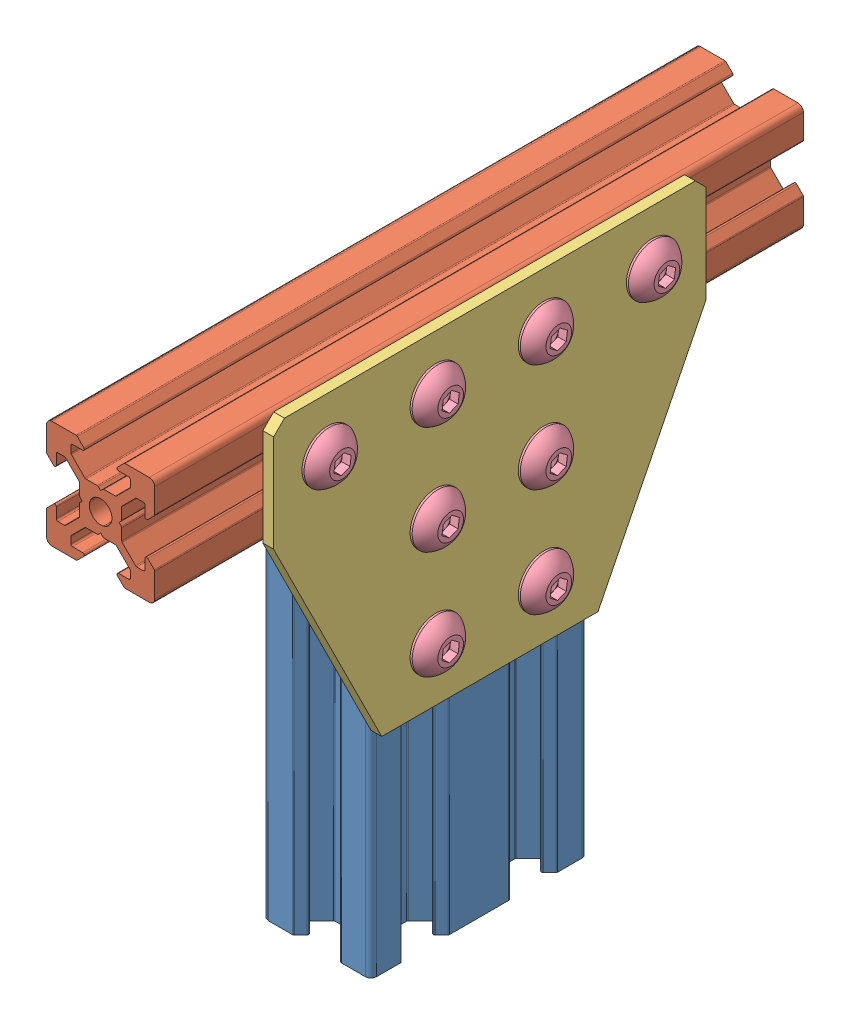
SolidWorks assembly Т-пластина 20 серия 4х3 8отв 60х80х2 усил СБ, configuration По умолчанию. Lengths in mm.
Overall size (24.75 100 120).
11 component instances, 4 part files, 25 mates.
Components (placement in the parent):
- 204090-1: 204090 [По умолчанию] at (-10 0 -10) x (0 0 -1) z (0 1 0) size (40 20 80)
- 2020100-1: 2020100 [По умолчанию] at (-10 90 -80) size (20 20 120)
- Т-пластина 20 серия 4х3 8отв 60х80х2 усил.-1: Т-пластина 20 серия 4х3 8отв 60х80х2 усил. [По умолчанию] at (0 40 -20) x (0 0 -1) z (0 -1 0) size (80 2 60)
- socket button head screw_iso-1: socket button head screw_iso [ISO 7380 - M5 x 10 - 10N] at (4.75 90 10) x (-1 0 0) z (0 0.924225 0.381849) size (12.75 9.5 9.5)
- socket button head screw_iso-2: socket button head screw_iso [ISO 7380 - M5 x 10 - 10N] at (4.75 90 -10) x (-1 0 0) z (0 0.924225 0.381849) size (12.75 9.5 9.5)
- socket button head screw_iso-3: socket button head screw_iso [ISO 7380 - M5 x 10 - 10N] at (4.75 90 -30) x (-1 0 0) z (0 0.924225 0.381849) size (12.75 9.5 9.5)
- socket button head screw_iso-4: socket button head screw_iso [ISO 7380 - M5 x 10 - 10N] at (4.75 90 -50) x (-1 0 0) z (0 0.924225 0.381849) size (12.75 9.5 9.5)
- socket button head screw_iso-5: socket button head screw_iso [ISO 7380 - M5 x 10 - 10N] at (4.75 70 -10) x (-1 0 0) z (0 0.924225 0.381849) size (12.75 9.5 9.5)
- socket button head screw_iso-6: socket button head screw_iso [ISO 7380 - M5 x 10 - 10N] at (4.75 70 -30) x (-1 0 0) z (0 0.924225 0.381849) size (12.75 9.5 9.5)
- socket button head screw_iso-7: socket button head screw_iso [ISO 7380 - M5 x 10 - 10N] at (4.75 50 -10) x (-1 0 0) z (0 0.924225 0.381849) size (12.75 9.5 9.5)
- socket button head screw_iso-8: socket button head screw_iso [ISO 7380 - M5 x 10 - 10N] at (4.75 50 -30) x (-1 0 0) z (0 0.924225 0.381849) size (12.75 9.5 9.5)
Mates (geometry in assembly coordinates):
- Совпадение1: coincident anti-aligned: plane of 204090-1 through (-10 0 -10) normal (0 -1 0)
- Совпадение2: coincident aligned: plane of 204090-1 through (0 80 -25.6) normal (1 0 0)
- Совпадение3: coincident aligned: plane of 204090-1 through (-20 80 0) normal (0 0 1)
- Совпадение4: coincident anti-aligned: plane of 204090-1 through (-10 80 -10) normal (0 1 0); plane of 2020100-1 through (0 80 40) normal (0 -1 0)
- Совпадение5: coincident aligned: plane of 204090-1 through (0 80 0) normal (1 0 0); plane of 2020100-1 through (0 80 40) normal (1 0 0)
- Совпадение6: coincident anti-aligned: plane of 204090-1 through (0 80 -25.6) normal (1 0 0); plane of Т-пластина 20 серия 4х3 8отв 60х80х2 усил.-1 through (0 40 -20) normal (-1 0 0)
- Совпадение7: coincident aligned: plane of 2020100-1 through (0 100 40) normal (0 1 0); plane of Т-пластина 20 серия 4х3 8отв 60х80х2 усил.-1 through (2 100 20) normal (0 1 0)
- Совпадение8: coincident: plane of 204090-1 through (0 80 0) normal (0 0 1); line of Т-пластина 20 серия 4х3 8отв 60х80х2 усил.-1 through (2 40 0) axis (-1 0 0)
- Расстояние1: distance = 20 mm aligned: plane of Т-пластина 20 серия 4х3 8отв 60х80х2 усил.-1 through (2 100 20) normal (0 0 1); plane of 2020100-1 through (-10 90 40) normal (0 0 1)
- Концентричный1: concentric aligned: cylinder of Т-пластина 20 серия 4х3 8отв 60х80х2 усил.-1 through (2 90 10) axis (1 0 0) radius 2.75; cylinder of socket button head screw_iso-1 through (4.75 90 10) axis (1 0 0) radius 4.75
- Совпадение10: coincident anti-aligned: plane of Т-пластина 20 серия 4х3 8отв 60х80х2 усил.-1 through (2 40 -20) normal (1 0 0); plane of socket button head screw_iso-1 through (2 89.0454 12.3106) normal (-1 0 0)
- Концентричный2: concentric aligned: cylinder of Т-пластина 20 серия 4х3 8отв 60х80х2 усил.-1 through (2 90 -10) axis (1 0 0) radius 2.75; cylinder of socket button head screw_iso-2 through (4.75 90 -10) axis (1 0 0) radius 4.75
- Совпадение11: coincident anti-aligned: plane of Т-пластина 20 серия 4х3 8отв 60х80х2 усил.-1 through (2 40 -20) normal (1 0 0); plane of socket button head screw_iso-2 through (2 89.0454 -7.6894) normal (-1 0 0)
- Концентричный3: concentric aligned: cylinder of Т-пластина 20 серия 4х3 8отв 60х80х2 усил.-1 through (2 90 -30) axis (1 0 0) radius 2.75; cylinder of socket button head screw_iso-3 through (4.75 90 -30) axis (1 0 0) radius 4.75
- Совпадение12: coincident anti-aligned: plane of Т-пластина 20 серия 4х3 8отв 60х80х2 усил.-1 through (2 40 -20) normal (1 0 0); plane of socket button head screw_iso-3 through (2 89.0454 -27.6894) normal (-1 0 0)
- Концентричный4: concentric aligned: cylinder of Т-пластина 20 серия 4х3 8отв 60х80х2 усил.-1 through (2 90 -50) axis (1 0 0) radius 2.75; cylinder of socket button head screw_iso-4 through (4.75 90 -50) axis (1 0 0) radius 4.75
- Совпадение13: coincident anti-aligned: plane of Т-пластина 20 серия 4х3 8отв 60х80х2 усил.-1 through (2 40 -20) normal (1 0 0); plane of socket button head screw_iso-4 through (2 89.0454 -47.6894) normal (-1 0 0)
- Концентричный5: concentric aligned: cylinder of Т-пластина 20 серия 4х3 8отв 60х80х2 усил.-1 through (2 70 -10) axis (1 0 0) radius 2.75; cylinder of socket button head screw_iso-5 through (4.75 70 -10) axis (1 0 0) radius 4.75
- Совпадение14: coincident anti-aligned: plane of Т-пластина 20 серия 4х3 8отв 60х80х2 усил.-1 through (2 40 -20) normal (1 0 0); plane of socket button head screw_iso-5 through (2 69.0454 -7.6894) normal (-1 0 0)
- Концентричный6: concentric aligned: cylinder of Т-пластина 20 серия 4х3 8отв 60х80х2 усил.-1 through (2 70 -30) axis (1 0 0) radius 2.75; cylinder of socket button head screw_iso-6 through (4.75 70 -30) axis (1 0 0) radius 4.75
- Совпадение15: coincident anti-aligned: plane of Т-пластина 20 серия 4х3 8отв 60х80х2 усил.-1 through (2 40 -20) normal (1 0 0); plane of socket button head screw_iso-6 through (2 69.0454 -27.6894) normal (-1 0 0)
- Концентричный7: concentric aligned: cylinder of Т-пластина 20 серия 4х3 8отв 60х80х2 усил.-1 through (2 50 -10) axis (1 0 0) radius 2.75; cylinder of socket button head screw_iso-7 through (4.75 50 -10) axis (1 0 0) radius 4.75
- Совпадение16: coincident anti-aligned: plane of Т-пластина 20 серия 4х3 8отв 60х80х2 усил.-1 through (2 40 -20) normal (1 0 0); plane of socket button head screw_iso-7 through (2 49.0454 -7.6894) normal (-1 0 0)
- Концентричный8: concentric aligned: cylinder of Т-пластина 20 серия 4х3 8отв 60х80х2 усил.-1 through (2 50 -30) axis (1 0 0) radius 2.75; cylinder of socket button head screw_iso-8 through (4.75 50 -30) axis (1 0 0) radius 4.75
- Совпадение17: coincident anti-aligned: plane of Т-пластина 20 серия 4х3 8отв 60х80х2 усил.-1 through (2 40 -20) normal (1 0 0); plane of socket button head screw_iso-8 through (2 49.0454 -27.6894) normal (-1 0 0)
